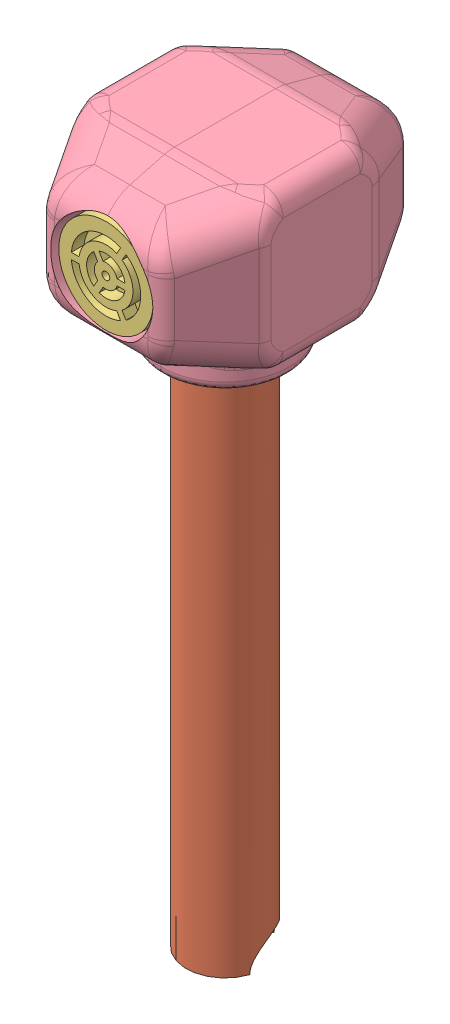
SolidWorks assembly SENSOR, SONAR, TOP ASSY, configuration Default. Lengths in mm.
Overall size (31.75 118.28 40.64).
6 component instances, 4 part files, 16 mates.
Components (placement in the parent):
- SENSOR, SONAR, MOUNTING BLOCK-1: SENSOR, SONAR, MOUNTING BLOCK [Default] at origin size (22.1 19.9 6.35)
- ACUATORS, STEPPER, SHAFT, SONAR-1: ACUATORS, STEPPER, SHAFT, SONAR [Default] at (0 -105.2 0) x (0.44514 0 0.895461) z (-0.895461 0 0.44514) size (12.7 95.79 12.7)
- SENSOR, SONAR, Maxbotix EZ4-1: SENSOR, SONAR, Maxbotix EZ4 [Default] at (0 0 3.175) x (0 -1 0) z (0 0 1) size (19.9 22.1 16.38)
- SENSOR, SONAR, Maxbotix EZ4-2: SENSOR, SONAR, Maxbotix EZ4 [Default] at (0 0 -3.175) x (0 -1 0) z (0 0 -1) size (19.9 22.1 16.38)
- SENSOR, SONAR, COVER-1: SENSOR, SONAR, COVER [Default] at origin size (15.88 31.75 40.64)
- SENSOR, SONAR, COVER-2: SENSOR, SONAR, COVER [Default] x (-1 0 0) z (0 0 -1) size (15.88 31.75 40.64)
Mates (geometry in assembly coordinates):
- Coincident1: coincident anti-aligned: plane of SENSOR, SONAR, MOUNTING BLOCK-1 through (11.05 9.95 3.175) normal (0 0 1); plane of SENSOR, SONAR, Maxbotix EZ4-1 through (11.05 -9.95 3.175) normal (0 0 -1)
- Coincident2: coincident anti-aligned: plane of SENSOR, SONAR, MOUNTING BLOCK-1 through (11.05 9.95 -3.175) normal (0 0 -1); plane of SENSOR, SONAR, Maxbotix EZ4-2 through (-11.05 -9.95 -3.175) normal (0 0 1)
- Concentric1: concentric aligned: cylinder of SENSOR, SONAR, MOUNTING BLOCK-1 through (0 2.75 0) axis (0 -1 0) radius 1.0325; cylinder of ACUATORS, STEPPER, SHAFT, SONAR-1 through (0 -9.95 0) axis (0 -1 0) radius 5.5563
- Coincident8: coincident aligned: plane of SENSOR, SONAR, MOUNTING BLOCK-1 through (0 0 0) normal (0 1 0); plane of assembly through (0 0 0) normal (0 1 0)
- Coincident9: coincident aligned: plane of SENSOR, SONAR, MOUNTING BLOCK-1 through (0 0 0) normal (0 0 1); plane of assembly through (0 0 0) normal (0 0 1)
- Coincident10: coincident aligned: plane of SENSOR, SONAR, MOUNTING BLOCK-1 through (0 0 0) normal (1 0 0); plane of assembly through (0 0 0) normal (1 0 0)
- Concentric2: concentric anti-aligned: cylinder of SENSOR, SONAR, Maxbotix EZ4-2 through (0 0 -19.558) axis (0 0 1) radius 7.747; cylinder of SENSOR, SONAR, COVER-1 through (0 0 20.32) axis (0 0 -1) radius 8.382
- Concentric4: concentric aligned: cylinder of SENSOR, SONAR, Maxbotix EZ4-2 through (0 0 -19.558) axis (0 0 1) radius 7.747; cylinder of SENSOR, SONAR, COVER-2 through (0 0 -20.32) axis (0 0 1) radius 8.382
- Concentric5: concentric anti-aligned: cylinder of SENSOR, SONAR, COVER-1 through (-9.525 9.9695 11.1125) axis (1 0 0) radius 0.889; cylinder of SENSOR, SONAR, COVER-2 through (9.525 9.9695 11.1125) axis (-1 0 0) radius 0.889
- Coincident11: coincident anti-aligned: plane of SENSOR, SONAR, COVER-2 through (0 0 0) normal (0 0 -1); plane of assembly through (0 0 0) normal (0 0 1)
- Parallel1: parallel aligned: plane of SENSOR, SONAR, COVER-2; plane of assembly through (0 0 0) normal (0 1 0)
- Coincident12: coincident anti-aligned: plane of SENSOR, SONAR, MOUNTING BLOCK-1 through (-11.05 -9.95 3.175) normal (0 -1 0); plane of ACUATORS, STEPPER, SHAFT, SONAR-1 through (0 -9.95 0) normal (0 1 0)
- Coincident15: coincident aligned: plane of SENSOR, SONAR, MOUNTING BLOCK-1 through (-11.05 9.95 3.175) normal (0 1 0); plane of SENSOR, SONAR, Maxbotix EZ4-2 through (11.05 9.95 -4.7625) normal (0 1 0)
- Coincident16: coincident aligned: plane of SENSOR, SONAR, MOUNTING BLOCK-1 through (11.05 -9.95 3.175) normal (1 0 0); plane of SENSOR, SONAR, Maxbotix EZ4-2 through (11.05 9.95 -4.7625) normal (1 0 0)
- Coincident17: coincident aligned: plane of SENSOR, SONAR, MOUNTING BLOCK-1 through (-11.05 9.95 3.175) normal (0 1 0); plane of SENSOR, SONAR, Maxbotix EZ4-1 through (-11.05 9.95 4.7625) normal (0 1 0)
- Coincident18: coincident aligned: plane of SENSOR, SONAR, MOUNTING BLOCK-1 through (-11.05 -9.95 3.175) normal (-1 0 0); plane of SENSOR, SONAR, Maxbotix EZ4-1 through (-11.05 9.95 4.7625) normal (-1 0 0)
